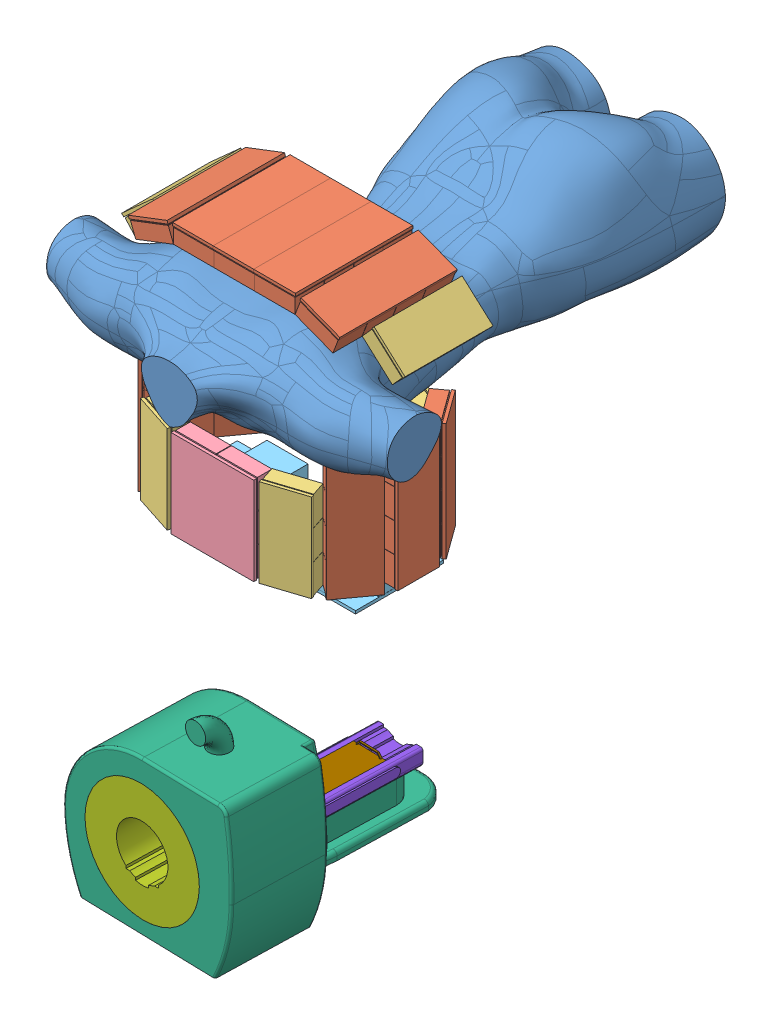
SolidWorks assembly Assem1, configuration Default. Lengths in mm.
Overall size (931.39 478.22 1293.92).
31 component instances, 9 part files, 0 mates.
Components (placement in the parent):
- woman body-1: woman body [Default] at (325.4407 484.4544 221.086) size (637.83 301.02 817.55)
- Detector_posterial-1: Detector_posterial [Default] at (222.7152 725.2068 938.4124) x (1 0 0) z (0 0 -1) size (482.7 103.57 200)
  - 1Detector-1: 1Detector [Default] at (83.9721 85.3161 150.6758) size (71 32 200)
  - 1Detector-2: 1Detector [Default] at (152.9721 85.3161 150.6758) size (71 32 200)
  - 1Detector-3: 1Detector [Default] at (14.9721 85.3161 150.6758) size (71 32 200)
  - 1Detector-4: 1Detector [Default] at (-63.2042 99.8052 150.6758) x (0.93358 -0.358368 0) z (0 0 1) size (71 32 200)
  - 1Detector-5: 1Detector [Default] at (231.1484 99.8052 150.6758) x (0.93358 0.358368 0) z (0 0 1) size (71 32 200)
  - 1Detector_3modules-1: 1Detector_3modules [Default] at (-130.9957 141.3479 175.6758) x (0.743145 -0.669131 0) z (0 0 1) size (71 32 150)
  - 1Detector_3modules-2: 1Detector_3modules [Default] at (298.9398 141.3479 175.6758) x (0.743145 0.669131 0) z (0 0 1) size (71 32 150)
- Detector1n2_2-1: Detector1n2_2 [Default] at (262.1834 410.9569 572.8392) x (1 0 0) z (0 -1 0) size (495.24 340.33 230.2)
  - top_bottomDetector2-1: top_bottomDetector2 [Default] at (5.3043 60.2155 74.3483) size (141 32 149.74)
  - CshapedDetector2-1: CshapedDetector2 [Default] at (104.3454 -76.5763 -85.899) x (0.951057 0.309017 0) z (0 0 1) size (177.89 270.84 200)
    - 1Detector-2: 1Detector [Default] at (173.0714 153.2337 184.2598) x (0.809017 0.587785 0) z (0 0 1) size (71 32 200)
    - 1Detector-4: 1Detector [Default] at (223.2683 222.3237 184.2598) x (0.309017 0.951057 0) z (0 0 1) size (71 32 200)
    - 1Detector-5: 1Detector [Default] at (223.2683 307.7237 184.2598) x (-0.309017 0.951057 0) z (0 0 1) size (71 32 200)
    - 1Detector_3modules-1: 1Detector_3modules [Default] at (91.8512 126.8436 209.2598) size (71 32 150)
    - 1Detector_3modules-2: 1Detector_3modules [Default] at (173.0714 376.8138 209.2598) x (-0.809017 0.587785 0) z (0 0 1) size (71 32 150)
  - CshapedDetector2-2: CshapedDetector2 [Default] at (-23.7368 484.2959 -85.899) x (-0.951057 -0.309017 0) z (0 0 1) size (177.89 270.84 200)
    - 1Detector-2: 1Detector [Default] at (173.0714 153.2337 184.2598) x (0.809017 0.587785 0) z (0 0 1) size (71 32 200)
    - 1Detector-4: 1Detector [Default] at (223.2683 222.3237 184.2598) x (0.309017 0.951057 0) z (0 0 1) size (71 32 200)
    - 1Detector-5: 1Detector [Default] at (223.2683 307.7237 184.2598) x (-0.309017 0.951057 0) z (0 0 1) size (71 32 200)
    - 1Detector_3modules-1: 1Detector_3modules [Default] at (91.8512 126.8436 209.2598) size (71 32 150)
    - 1Detector_3modules-2: 1Detector_3modules [Default] at (173.0714 376.8138 209.2598) x (-0.809017 0.587785 0) z (0 0 1) size (71 32 150)
  - top_bottomDetector2-2: top_bottomDetector2 [Default] at (75.3043 347.5042 74.3483) x (-1 0 0) z (0 0 1) size (141 32 149.74)
  - Detector2-1: Detector2 [Default] at (-50.3758 204.3598 228.5608) x (1 0 0) z (0 1 0) size (170 30.5 151.04)
  - Detector2-2: Detector2 [Default] at (130.9844 204.3598 228.5608) x (1 0 0) z (0 1 0) size (170 30.5 151.04)
- MRI scanner-2: MRI scanner [Default] at (960.129 95.9283 1613.4633) x (-0.999657 0 -0.026177) z (0.026177 0 -0.999657) size (294.65 316.99 467.51)
  - Base Frame-1: Base Frame [Default] at (215.0742 187.8159 122.1083) size (294.65 316.99 467.51)
  - Center Part-1: Center Part [Default] at (215.0742 187.8159 130.1083) size (200 200 211.2)
  - Bed Base-1: Bed Base [Default] at (186.6426 152.9355 330.1083) size (86.86 30 220)
  - Moving Bed-1: Moving Bed [Default] at (186.6426 152.9355 280.0733) size (56.86 21.3 220)
